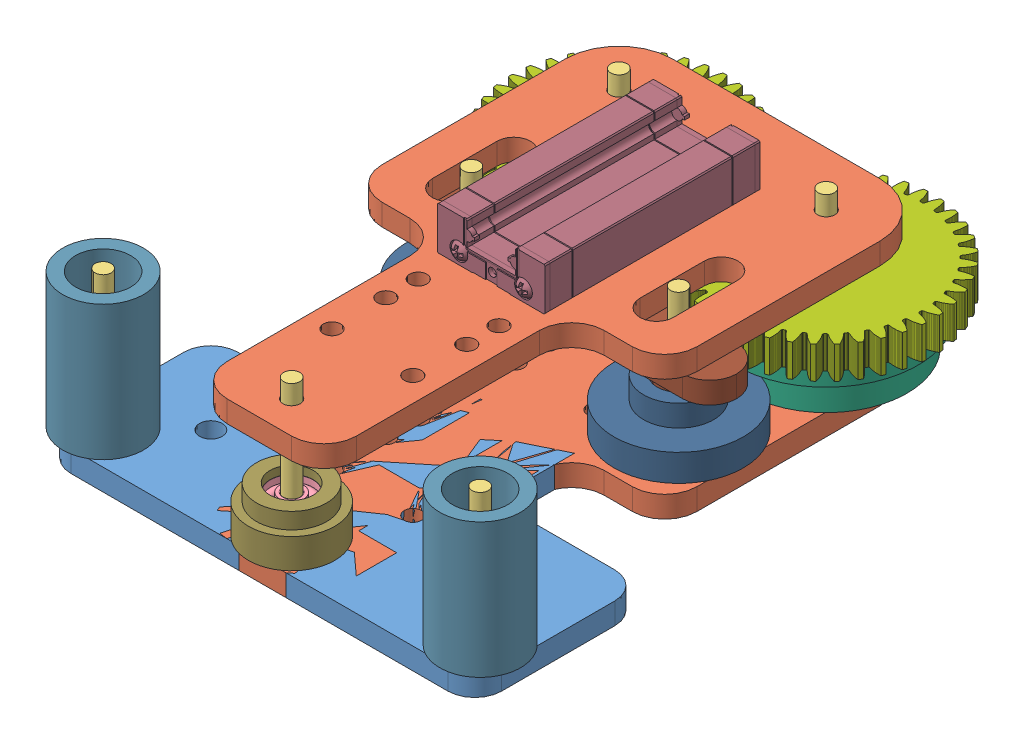
SolidWorks assembly tape, configuration Default. Lengths in mm.
Overall size (87.44 38.85 112.93).
42 component instances, 14 part files, 19 mates.
Components (placement in the parent):
- Part16-1: Part16 [Default] at (31.3412 39.2834 57.1025) size (80 4 46)
- tape_assem-2: tape_assem [Default] at (-3.8016 -10.8052 -37.5983) size (83.07 38.85 111.04)
  - Part1-1: Part1 [Default] at (35.1427 50.0885 74.7008) size (58.5 4 96)
  - pan head cross recess screw_iso-3: pan head cross recess screw_iso [ISO 7045 - M3 x 30 - Z - 25N] at (15.8927 47.6885 34.7008) x (0 1 0) z (-0.573423 0 0.819259) size (32.35 5.6 5.6)
  - pan head cross recess screw_iso-4: pan head cross recess screw_iso [ISO 7045 - M3 x 30 - Z - 25N] at (54.3927 47.6885 34.7008) x (0 1 0) z (0.962344 0 -0.271836) size (32.35 5.6 5.6)
  - angular contact ball bearing_68_iso-2: angular contact ball bearing_68_iso [ISO 15 ABB - 023 - Full,SI,NC,Full_68] at (15.8927 59.5885 34.7008) x (0 1 0) z (0 0 1) size (4 10 10)
  - angular contact ball bearing_68_iso-3: angular contact ball bearing_68_iso [ISO 15 ABB - 023 - Full,SI,NC,Full_68] at (54.3927 59.5885 34.7008) x (0 1 0) z (0 0 1) size (4 10 10)
  - Part10-1: Part10 [Default] at (15.8927 54.0885 34.7008) size (7 3.5 7)
  - Part10-2: Part10 [Default] at (54.3927 54.0885 34.7008) size (7 3.5 7)
  - Part2-1: Part2 [Default] at (15.8927 54.5885 34.7008) x (0.986053 0 -0.166431) z (0.166431 0 0.986053) size (34 8.5 34)
  - Part9-1: Part9 [Default] at (15.8927 69.0885 34.7008) x (0.166431 0 0.986053) z (0 -1 0) size (39.9 39.9 6)
  - Part2-2: Part2 [Default] at (54.3927 54.5885 34.7008) x (0.996363 0 0.085209) z (-0.085209 0 0.996363) size (34 8.5 34)
  - Part9-2: Part9 [Default] at (54.3927 69.0885 34.7008) x (0.085209 0 -0.996363) z (0 -1 0) size (39.9 39.9 6)
  - Part11-1: Part11 [Default] at (15.8927 50.0885 62.1008) x (-1 0 0) z (0 0 -1) size (15 6.2 15)
  - Part11-2: Part11 [Default] at (54.3927 50.0885 62.1008) size (15 6.2 15)
  - pan head cross recess screw_iso-6: pan head cross recess screw_iso [ISO 7045 - M3 x 30 - Z - 25N] at (15.8927 45.6885 62.1008) x (0 1 0) z (0.493644 0 -0.869664) size (32.35 5.6 5.6)
  - pan head cross recess screw_iso-7: pan head cross recess screw_iso [ISO 7045 - M3 x 30 - Z - 25N] at (54.3927 45.6885 62.1008) x (0 1 0) z (0.829408 0 -0.558643) size (32.35 5.6 5.6)
  - Part12-1: Part12 [Default] at (54.3927 54.2885 62.1008) size (9 3.5 9)
  - Part12-2: Part12 [Default] at (15.8927 54.2885 62.1008) size (9 3.5 9)
  - angular contact ball bearing_68_iso-4: angular contact ball bearing_68_iso [ISO 15 ABB - 023 - 8,SI,NC,8_68] at (54.3927 67.0885 34.7008) x (0 -1 0) z (0 0 1) size (4 10 10)
  - angular contact ball bearing_68_iso-5: angular contact ball bearing_68_iso [ISO 15 ABB - 023 - 8,SI,NC,8_68] at (15.8927 67.0885 34.7008) x (0 1 0) z (0 0 1) size (4 10 10)
  - angular contact ball bearing_68_iso-6: angular contact ball bearing_68_iso [ISO 15 ABB - 023 - 8,SI,NC,8_68] at (15.8927 59.7885 62.1008) x (0 1 0) z (-0.546944 0 0.837169) size (4 10 10)
  - angular contact ball bearing_68_iso-7: angular contact ball bearing_68_iso [ISO 15 ABB - 023 - 8,SI,NC,8_68] at (54.3927 59.7885 62.1008) x (0 1 0) z (0 0 1) size (4 10 10)
  - Part13-1: Part13 [Default] at (15.8927 54.7885 62.1008) x (-0.600319 0 -0.79976) z (0.79976 0 -0.600319) size (24 9 24)
  - Part13-2: Part13 [Default] at (54.3927 54.7885 62.1008) x (0.670058 0 0.742308) z (-0.742308 0 0.670058) size (24 9 24)
  - Part14-1: Part14 [Default] at (35.1427 69.2885 62.1008) x (-1 0 0) z (0 0 1) size (60 7.5 10)
  - pan head cross recess screw_iso-8: pan head cross recess screw_iso [ISO 7045 - M3 x 30 - Z - 25N] at (35.1427 47.6885 114.7008) x (0 1 0) z (-0.573423 0 0.819259) size (32.35 5.6 5.6)
  - Part1-2: Part1 [Default] at (35.1427 72.5885 74.7008) size (58.5 4 96)
  - Part10-3: Part10 [Default] at (54.3927 69.0885 34.7008) x (0.984224 0 -0.176926) z (0.176926 0 0.984224) size (7 3.5 7)
  - Part10-4: Part10 [Default] at (15.8927 69.0885 34.7008) size (7 3.5 7)
  - angular contact ball bearing_68_iso-10: angular contact ball bearing_68_iso [ISO 15 ABB - 023 - Full,SI,NC,Full_68] at (35.1427 59.5885 114.7008) x (0 1 0) z (0 0 1) size (4 10 10)
  - Part10-5: Part10 [Default] at (35.1427 54.0885 114.7008) size (7 3.5 7)
  - Part15-1: Part15 [Default] at (35.1427 54.5885 114.7008) x (0.999983 0 -0.005913) z (0.005913 0 0.999983) size (16 8.5 16)
  - v1_MGN9-H-1: v1_MGN9-H [По умолчанию] at (35.1427 80.5885 57.7008) x (-1 0 0) z (0 0 1) size (20 8 41.29)
- pan head cross recess screw_iso-1: pan head cross recess screw_iso [ISO 7045 - M3 x 30 - Z - 25N] at (66.3412 36.8834 77.1025) x (0 1 0) z (0.836677 0 0.547696) size (32.35 5.6 5.6)
- pan head cross recess screw_iso-2: pan head cross recess screw_iso [ISO 7045 - M3 x 30 - Z - 25N] at (-3.6588 36.8834 77.1025) x (0 1 0) z (0.977218 0 0.212239) size (32.35 5.6 5.6)
- Part17-1: Part17 [Default] at (-3.6588 43.7834 77.1025) size (15 25 15)
- Part10-1: Part10 [Default] at (66.3412 46.7834 77.1025) x (-0.837169 0 -0.546944) z (-0.546944 0 0.837169) size (7 3.5 7)
- Part10-2: Part10 [Default] at (-3.6588 46.7834 77.1025) x (-0.837169 0 -0.546944) z (-0.546944 0 0.837169) size (7 3.5 7)
- angular contact ball bearing_68_iso-1: angular contact ball bearing_68_iso [ISO 15 ABB - 023 - Full,SI,NC,Full_68] at (66.3412 48.7834 77.1025) x (0 1 0) z (0 0 1) size (4 10 10)
- angular contact ball bearing_68_iso-2: angular contact ball bearing_68_iso [ISO 15 ABB - 023 - Full,SI,NC,Full_68] at (-3.6588 48.7834 77.1025) x (0 -1 0) z (0 0 1) size (4 10 10)
- Part17-2: Part17 [Default] at (66.3412 43.7834 77.1025) x (0.909923 0 -0.414777) z (0.414777 0 0.909923) size (15 25 15)
Mates (geometry in assembly coordinates):
- Coincident1: coincident aligned: plane of Part16-1 through (-3.6588 43.2834 78.1025) normal (0 1 0); plane of tape_assem-2/Part1-1 through (12.0912 43.2834 -2.8975) normal (0 1 0)
- Concentric1: concentric aligned: cylinder of Part16-1 through (38.8412 43.2834 46.1025) axis (0 -1 0) radius 1.6; cylinder of tape_assem-2/Part1-1 through (38.8412 43.2834 46.1025) axis (0 -1 0) radius 1.6
- Concentric2: concentric aligned: cylinder of Part16-1 through (23.8412 43.2834 46.1025) axis (0 -1 0) radius 1.6; cylinder of tape_assem-2/Part1-1 through (23.8412 43.2834 46.1025) axis (0 -1 0) radius 1.6
- Concentric3: concentric aligned: cylinder of Part16-1 through (-3.6588 43.2834 77.1025) axis (0 -1 0) radius 1.6; cylinder of pan head cross recess screw_iso-2 through (-3.6588 11.4834 77.1025) axis (0 -1 0) radius 1.5
- Coincident3: coincident anti-aligned: plane of Part16-1 through (-3.6588 39.2834 78.1025) normal (0 -1 0); plane of pan head cross recess screw_iso-2 through (-3.9772 39.2834 78.5683) normal (0 1 0)
- Concentric4: concentric aligned: cylinder of Part16-1 through (66.3412 43.2834 77.1025) axis (0 -1 0) radius 1.6; cylinder of pan head cross recess screw_iso-1 through (66.3412 11.4834 77.1025) axis (0 -1 0) radius 1.5
- Coincident4: coincident anti-aligned: plane of Part16-1 through (-3.6588 39.2834 78.1025) normal (0 -1 0); plane of pan head cross recess screw_iso-1 through (65.5196 39.2834 78.3575) normal (0 1 0)
- Coincident5: coincident anti-aligned: plane of Part16-1 through (-3.6588 43.2834 78.1025) normal (0 1 0); plane of Part10-2 through (-3.6588 43.2834 77.1025) normal (0 -1 0)
- Concentric5: concentric anti-aligned: cylinder of pan head cross recess screw_iso-2 through (-3.6588 11.4834 77.1025) axis (0 -1 0) radius 1.5; cylinder of Part10-2 through (-3.6588 43.2834 77.1025) axis (0 1 0) radius 1.6
- Coincident6: coincident anti-aligned: plane of Part16-1 through (-3.6588 43.2834 78.1025) normal (0 1 0); plane of Part10-1 through (66.3412 43.2834 77.1025) normal (0 -1 0)
- Concentric6: concentric anti-aligned: cylinder of pan head cross recess screw_iso-1 through (66.3412 11.4834 77.1025) axis (0 -1 0) radius 1.5; cylinder of Part10-1 through (66.3412 43.2834 77.1025) axis (0 1 0) radius 1.6
- Coincident7: coincident anti-aligned: plane of Part10-2 through (-3.6588 46.7834 77.1025) normal (0 1 0); plane of angular contact ball bearing_68_iso-2 through (-2.0088 46.7834 77.1025) normal (0 -1 0)
- Concentric7: concentric aligned: cylinder of pan head cross recess screw_iso-2 through (-3.6588 11.4834 77.1025) axis (0 -1 0) radius 1.5; cylinder of angular contact ball bearing_68_iso-2 through (-3.6588 69.4209 77.1025) axis (0 -1 0) radius 1.5
- Coincident8: coincident anti-aligned: plane of Part17-1 through (-3.6588 50.7834 77.1025) normal (0 -1 0); plane of angular contact ball bearing_68_iso-2 through (0.6162 50.7834 77.1025) normal (0 1 0)
- Concentric8: concentric aligned: cylinder of Part17-1 through (-3.6588 50.7834 77.1025) axis (0 -1 0) radius 5.1; cylinder of angular contact ball bearing_68_iso-2 through (-3.6588 69.4209 77.1025) axis (0 -1 0) radius 5
- Concentric9: concentric anti-aligned: cylinder of pan head cross recess screw_iso-1 through (66.3412 11.4834 77.1025) axis (0 -1 0) radius 1.5; cylinder of angular contact ball bearing_68_iso-1 through (66.3412 28.1459 77.1025) axis (0 1 0) radius 1.5
- Coincident9: coincident anti-aligned: plane of Part10-1 through (66.3412 46.7834 77.1025) normal (0 1 0); plane of angular contact ball bearing_68_iso-1 through (63.7912 46.7834 77.1025) normal (0 -1 0)
- Concentric10: concentric anti-aligned: cylinder of angular contact ball bearing_68_iso-1 through (66.3412 28.1459 77.1025) axis (0 1 0) radius 5; circle of Part17-2
- Coincident10: coincident anti-aligned: plane of angular contact ball bearing_68_iso-1 through (61.4912 50.7834 77.1025) normal (0 1 0); plane of Part17-2 through (66.3412 50.7834 77.1025) normal (0 -1 0)
